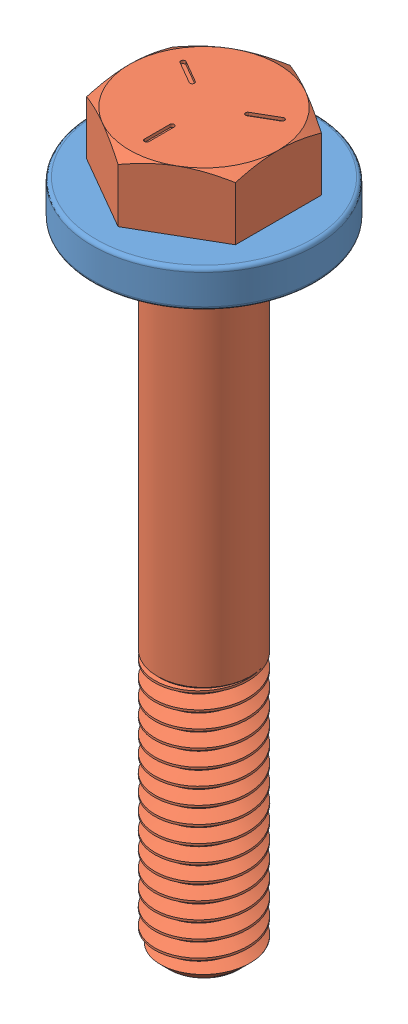
SolidWorks assembly t_slot_shortscrew_assy, configuration Default. Lengths in mm.
Overall size (19.05 62.83 19.05).
2 component instances, 2 part files, 5 mates.
Components (placement in the parent):
- 5-16x.75 oversize washer 91525A326_316 Stainless Steel Washer-1: 5-16x.75 oversize washer 91525A326_316 Stainless Steel Washer [91525A326] at (0 1.5875 0) x (1 0 0) z (0 -1 0) size (19.05 19.05 3.17)
- 5s16p18x2.25 bolt partial 91247A592_Medium-Strength Grade 5 Steel Hex Head Screw-1: 5s16p18x2.25 bolt partial 91247A592_Medium-Strength Grade 5 Steel Hex Head Screw [91247A592] at (0 -22.8203 0) x (0 -1 0) z (0.5 0 -0.866025) size (62.83 14.66 12.7)
Mates (geometry in assembly coordinates):
- Coincident1: coincident anti-aligned: plane of 5-16x.75 oversize washer 91525A326_316 Stainless Steel Washer-1 through (0 0 0) normal (0 -1 0)
- Coincident4: coincident aligned: plane of 5-16x.75 oversize washer 91525A326_316 Stainless Steel Washer-1 through (0 1.5875 0) normal (1 0 0)
- Concentric1: concentric aligned: cylinder of 5-16x.75 oversize washer 91525A326_316 Stainless Steel Washer-1 through (0 3.175 0) axis (0 -1 0) radius 4.3688; cylinder of 5s16p18x2.25 bolt partial 91247A592_Medium-Strength Grade 5 Steel Hex Head Screw-1 through (0 3.175 0) axis (0 -1 0) radius 3.9688
- Coincident5: coincident anti-aligned: plane of 5-16x.75 oversize washer 91525A326_316 Stainless Steel Washer-1 through (0 3.175 0) normal (0 1 0); plane of 5s16p18x2.25 bolt partial 91247A592_Medium-Strength Grade 5 Steel Hex Head Screw-1 through (0 3.175 -7.3323) normal (0 -1 0)
- Parallel1: parallel aligned: plane of 5s16p18x2.25 bolt partial 91247A592_Medium-Strength Grade 5 Steel Hex Head Screw-1 through (6.35 8.3344 3.6662) normal (1 0 0)
